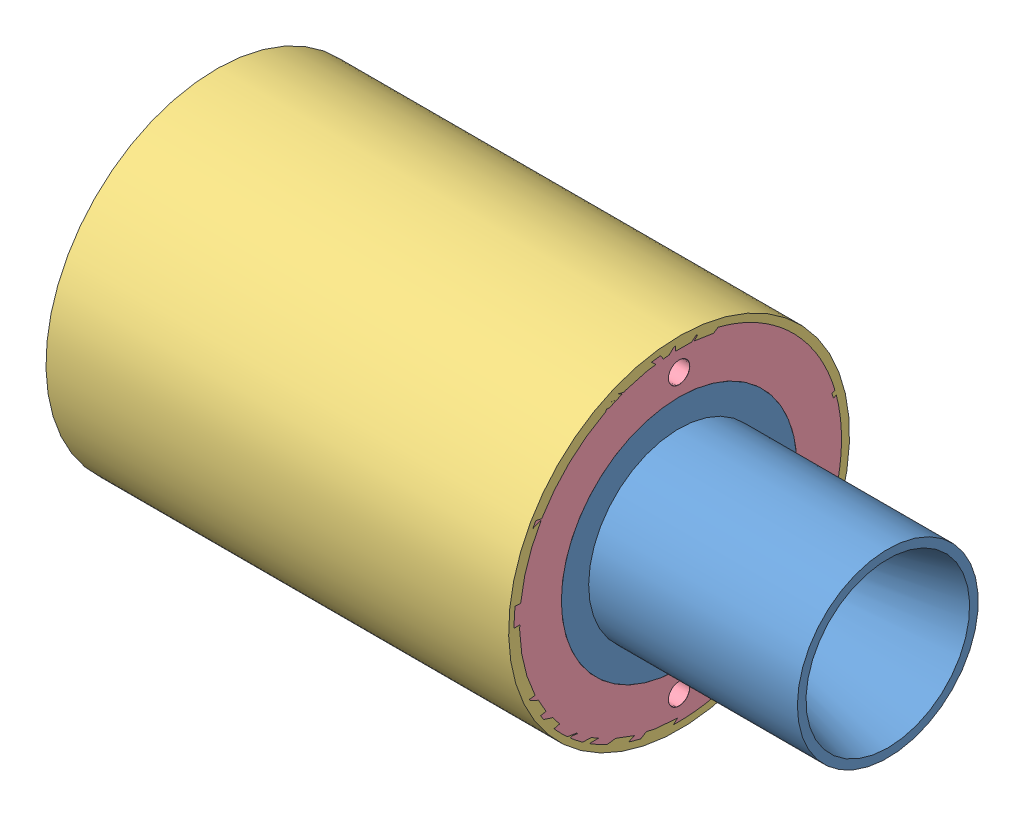
SolidWorks assembly Backup Nozzle, configuration Standard. Lengths in mm.
Overall size (193 128.82 128.82).
4 component instances, 4 part files, 8 mates.
Components (placement in the parent):
- Nozzle graphite-1: Nozzle graphite [Standard] at (87 0 0) x (1 0 0) z (0 0.621083 -0.783744) size (87 91.7 91.7)
- Thermal Insulation-1: Thermal Insulation [Standard] at (-100 0 0) x (0 -0.555608 -0.831444) z (1 0 0) size (91.69 91.69 112)
- Chamber 98mm-1: Chamber 98mm [Standard] at (-39.5 0 0) x (0 0.999039 -0.043829) z (0 0.043829 0.999039) size (98 133 98)
- Graphite nozzle retainer ring-1: Graphite nozzle retainer ring [Standard] at (17 0 0) x (0 -1 0) z (0 0 1) size (99.09 10.54 97.8)
Mates (geometry in assembly coordinates):
- Coincident1: coincident anti-aligned: plane of Nozzle graphite-1 through (0 -33.5913 -26.6196) normal (-1 0 0)
- Concentric1: concentric: cylinder of Nozzle graphite-1 through (87 0 0) axis (1 0 0) radius 26
- Concentric2: concentric anti-aligned: cylinder of Nozzle graphite-1 through (87 0 0) axis (1 0 0) radius 45.85; cylinder of Thermal Insulation-1 through (12 0 0) axis (-1 0 0) radius 45.847
- Concentric3: concentric anti-aligned: cylinder of Thermal Insulation-1 through (12 0 0) axis (-1 0 0) radius 45.847; cylinder of Chamber 98mm-1 through (-39.5 0 0) axis (1 0 0) radius 49
- Coincident4: coincident anti-aligned: plane of Nozzle graphite-1 through (12 -35.9347 -28.4767) normal (-1 0 0); plane of Thermal Insulation-1 through (12 0 0) normal (1 0 0)
- Concentric4: concentric anti-aligned: cylinder of Nozzle graphite-1 through (87 0 0) axis (1 0 0) radius 26; cylinder of Graphite nozzle retainer ring-1 through (17 0 0) axis (-1 0 0) radius 33.85
- Coincident5: coincident anti-aligned: plane of Nozzle graphite-1 through (17 -35.9347 -28.4767) normal (1 0 0); plane of Graphite nozzle retainer ring-1 through (17 33.85 0) normal (-1 0 0)
- Coincident6: coincident aligned: plane of Chamber 98mm-1 through (27 -45.8059 2.0096) normal (1 0 0); plane of Graphite nozzle retainer ring-1 through (27 33.85 0) normal (1 0 0)
